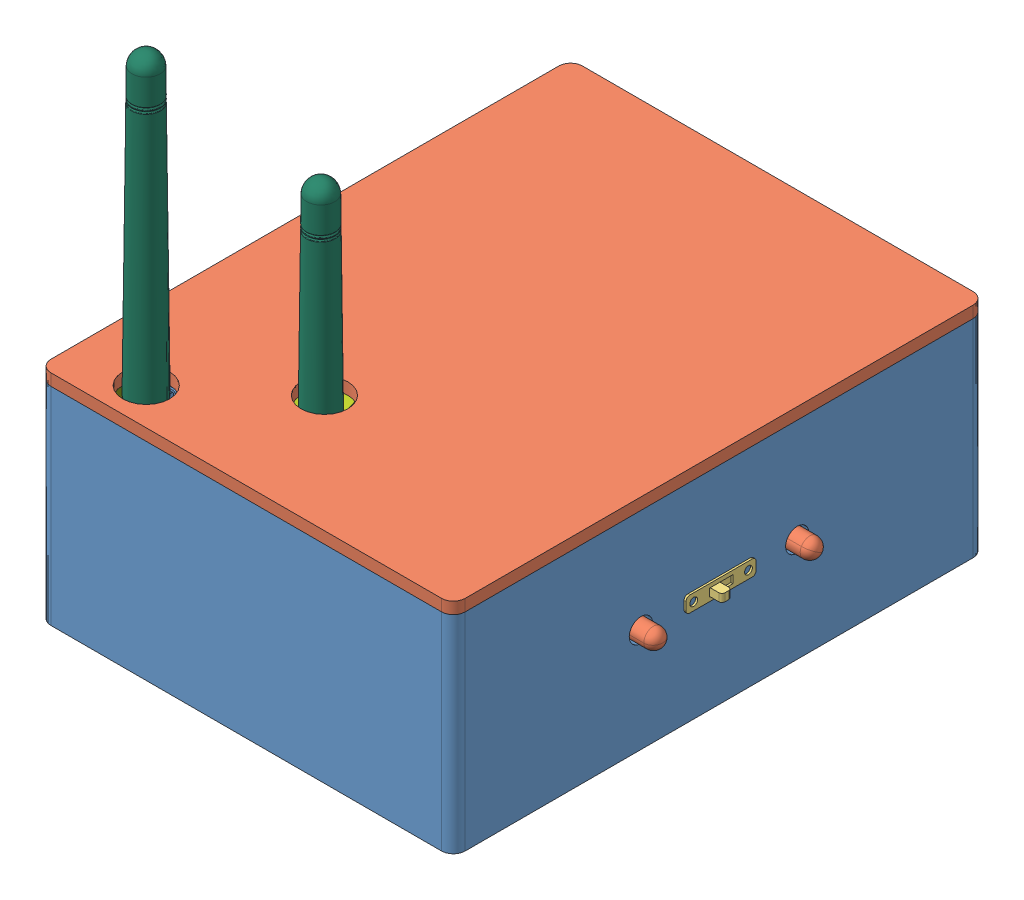
SolidWorks assembly antenna, configuration Défaut. Lengths in mm.
Overall size (111.65 135.1 136).
168 component instances, 75 part files, 26 mates.
Components (placement in the parent):
- lower_part_antenna-1: lower_part_antenna [Défaut] at (-3.6296 -22.8061 136) size (106 53 136)
- upper_part_antenna-1: upper_part_antenna [Défaut] at (-3.6296 27.1939 136) size (106 3 136)
- NUCLEO-F411RE.STEP-1: NUCLEO-F411RE.STEP [Défaut] at (-7.5295 -22.0211 161.2883) x (1 0 0) z (0 1 0) size (70 83.97 20.27)
  - NUCLEO-F411RE_PCB_Varsay_lan.STEP-1: NUCLEO-F411RE_PCB_Varsay_lan.STEP [Défaut] at origin size (70 82.5 1.5)
  - NUCLEO-F411RE_PCB_HOLEs_Varsay_lan.STEP-1: NUCLEO-F411RE_PCB_HOLEs_Varsay_lan.STEP [Défaut] at origin size (65.28 79.87 1.57)
  - NUCLEO-F411RE_PCB_TOP_Pads_Varsay_lan.STEP-1: NUCLEO-F411RE_PCB_TOP_Pads_Varsay_lan.STEP [Défaut] at origin size (59.94 77.1 0.04)
  - NUCLEO-F411RE_PCB_TOP_Solder_Varsay_lan.STEP-1: NUCLEO-F411RE_PCB_TOP_Solder_Varsay_lan.STEP [Défaut] at origin size (69.8 82.3 0.05)
  - NUCLEO-F411RE_PCB_BOTTOM_Pads_Varsay_lan.STEP-1: NUCLEO-F411RE_PCB_BOTTOM_Pads_Varsay_lan.STEP [Défaut] at origin size (31.1 70.87 0.04)
  - NUCLEO-F411RE_PCB_BOTTOM_Solder_Varsay_lan.STEP-1: NUCLEO-F411RE_PCB_BOTTOM_Solder_Varsay_lan.STEP [Défaut] at origin size (69.8 82.3 0.04)
  - NUCLEO-F411RE_PCB_TOP_Overlay_Varsay_lan.STEP-1: NUCLEO-F411RE_PCB_TOP_Overlay_Varsay_lan.STEP [Défaut] at origin size (68.09 77.67 0)
  - NUCLEO-F411RE_PCB_TOP_Designators_Varsay_lan.STEP-1: NUCLEO-F411RE_PCB_TOP_Designators_Varsay_lan.STEP [Défaut] at origin size (66.29 79.64 0)
  - NUCLEO-F411RE_PCB_BOTTOM_Overlay_Varsay_lan.STEP-1: NUCLEO-F411RE_PCB_BOTTOM_Overlay_Varsay_lan.STEP [Défaut] at origin size (40.11 80.77 0)
  - SAMTEC_SSQ-106-01-G-S_for_NUCLEO_Varsay_lan.STEP-1: SAMTEC_SSQ-106-01-G-S_for_NUCLEO_Varsay_lan.STEP [Défaut] at (-33.02 8.89 0.785) x (0 1 0) z (1 0 0) size (15.75 11.15 2.41)
  - SAMTEC_SSQ-108-01-G-S_for_NUCLEO_Varsay_lan.STEP-1: SAMTEC_SSQ-108-01-G-S_for_NUCLEO_Varsay_lan.STEP [Défaut] at (-33.02 29.21 0.785) x (0 1 0) z (1 0 0) size (20.83 11.15 2.41)
  - SAMTEC_SSQ-108-01-G-S_for_NUCLEO_Varsay_lan.STEP-2: SAMTEC_SSQ-108-01-G-S_for_NUCLEO_Varsay_lan.STEP [Défaut] at (15.24 11.43 0.785) x (0 1 0) z (1 0 0) size (20.83 11.15 2.41)
  - SAMTEC_SSQ-110-01-G-S_for_NUCLEO_Varsay_lan.STEP-1: SAMTEC_SSQ-110-01-G-S_for_NUCLEO_Varsay_lan.STEP [Défaut] at (15.24 35.814 0.785) x (0 1 0) z (1 0 0) size (25.91 11.15 2.41)
  - MOLEX_0678038020_for_NUCLEO.STEP-1: MOLEX_0678038020_for_NUCLEO.STEP [Défaut] at (3.1721 75.2975 0.785) x (-1 0 0) z (0 1 0) size (9.9 4.95 9)
  - SAMTEC_TSW-119-07-T-D_for_NUCLEO_Varsay_lan.STEP-1: SAMTEC_TSW-119-07-T-D_for_NUCLEO_Varsay_lan.STEP [Défaut] at (-39.37 25.4 0.785) x (0 -1 0) z (-1 0 0) size (48.26 17.95 5.08)
  - SAMTEC_TSW-119-07-T-D_for_NUCLEO_Varsay_lan.STEP-2: SAMTEC_TSW-119-07-T-D_for_NUCLEO_Varsay_lan.STEP [Défaut] at (21.59 25.4 0.785) x (0 -1 0) z (-1 0 0) size (48.26 17.95 5.08)
  - SAMTEC_TSW-102-07-T-S_for_NUCLEO_Varsay_lan.STEP-1: SAMTEC_TSW-102-07-T-S_for_NUCLEO_Varsay_lan.STEP [Défaut] at (-40.64 74.93 0.785) x (0 1 0) z (1 0 0) size (5.08 10.92 2.54)
  - SAMTEC_TSW-102-07-T-S_for_NUCLEO_Varsay_lan.STEP-2: SAMTEC_TSW-102-07-T-S_for_NUCLEO_Varsay_lan.STEP [Défaut] at (-31.75 59.055 0.785) x (0 -1 0) z (-1 0 0) size (5.08 10.92 2.54)
  - SAMTEC_TSW-102-07-T-S_for_NUCLEO_Varsay_lan.STEP-3: SAMTEC_TSW-102-07-T-S_for_NUCLEO_Varsay_lan.STEP [Défaut] at (-9.525 77.47 0.785) x (1 0 0) z (0 -1 0) size (5.08 10.92 2.54)
  - SAMTEC_TSW-102-07-T-S_for_NUCLEO_Varsay_lan.STEP-4: SAMTEC_TSW-102-07-T-S_for_NUCLEO_Varsay_lan.STEP [Défaut] at (-9.525 38.735 0.785) x (1 0 0) z (0 -1 0) size (5.08 10.92 2.54)
  - SAMTEC_TSW-102-07-T-S_for_NUCLEO_Varsay_lan.STEP-5: SAMTEC_TSW-102-07-T-S_for_NUCLEO_Varsay_lan.STEP [Défaut] at (22.86 74.93 0.785) x (0 -1 0) z (-1 0 0) size (5.08 10.92 2.54)
  - SAMTEC_TSW-103-07-T-S_for_NUCLEO_Varsay_lan.STEP-1: SAMTEC_TSW-103-07-T-S_for_NUCLEO_Varsay_lan.STEP [Défaut] at (1.905 45.085 0.785) x (1 0 0) z (0 -1 0) size (7.62 10.92 2.54)
  - SAMTEC_TSW-104-07-T-S_for_NUCLEO_Varsay_lan.STEP-1: SAMTEC_TSW-104-07-T-S_for_NUCLEO_Varsay_lan.STEP [Défaut] at (-21.59 73.66 0.785) x (0 1 0) z (1 0 0) size (10.16 10.92 2.54)
  - SAMTEC_TSW-106-07-T-S_for_NUCLEO_Varsay_lan.STEP-1: SAMTEC_TSW-106-07-T-S_for_NUCLEO_Varsay_lan.STEP [Défaut] at (-35.56 64.77 0.785) x (0 1 0) z (1 0 0) size (15.24 10.92 2.54)
  - MOLEX_90059-0007.STEP-1: MOLEX_90059-0007.STEP [Défaut] at (-21.59 76.2 5.75) x (0 1 0) z (1 0 0) size (5.1 4.85 2.54)
  - MOLEX_90059-0007.STEP-2: MOLEX_90059-0007.STEP [Défaut] at (-21.59 71.12 5.75) x (0 -1 0) z (-1 0 0) size (5.1 4.85 2.54)
  - ST_STM32F411RET6_Varsay_lan.STEP-1: ST_STM32F411RET6_Varsay_lan.STEP [Défaut] at (-11.4265 21.5935 0.785) x (-1 0 0) z (0 0 -1) size (12 12 1.6)
  - ST_STM32F103CBT6_Varsay_lan.STEP-1: ST_STM32F103CBT6_Varsay_lan.STEP [Défaut] at (-8.89 64.77 0.785) x (1 0 0) z (0 -1 0) size (9 1.6 9)
  - ESWITCH_TL3301SPF160QGBLK_Varsay_lan.STEP-1: ESWITCH_TL3301SPF160QGBLK_Varsay_lan.STEP [Défaut] at (-0.635 50.8 0.785) x (0 -1 0) z (-1 0 0) size (6 10.7 10)
  - ESWITCH_TL3301SPF160QGBLU_Varsay_lan.STEP-1: ESWITCH_TL3301SPF160QGBLU_Varsay_lan.STEP [Défaut] at (-17.145 50.8 0.785) x (0 1 0) z (1 0 0) size (6 10.7 10)
  - ST_STS7PF30L_Varsay_lan.STEP-1: ST_STS7PF30L_Varsay_lan.STEP [Défaut] at (17.145 60.325 0.785) x (-1 0 0) z (0 1 0) size (4.9 1.75 6)
  - ABRACON_ABL-8.000MHZ-B2_Varsay_lan.STEP-1: ABRACON_ABL-8.000MHZ-B2_Varsay_lan.STEP [Défaut] at (-18.41 63.4908 0.785) x (0 -1 0) z (-1 0 0) size (11.5 5.57 5)
  - ST_LD1117S50TR_Varsay_lan.STEP-1: ST_LD1117S50TR_Varsay_lan.STEP [Défaut] at (-14.6685 43.18 0.785) x (0 -1 0) z (-1 0 0) size (6.5 1.9 7)
  - ST_LD39050PU33R_Varsay_lan.STEP-1: ST_LD39050PU33R_Varsay_lan.STEP [Défaut] at (1.905 40.64 0.785) x (0 1 0) z (1 0 0) size (3 1 3)
  - ST_LD3985M33R_Varsay_lan.STEP-1: ST_LD3985M33R_Varsay_lan.STEP [Défaut] at (7.62 63.5 0.785) x (1 0 0) z (0 -1 0) size (2.95 1.45 2.8)
  - KEMET_T491B106K025AT_Varsay_lan.STEP-1: KEMET_T491B106K025AT_Varsay_lan.STEP [Défaut] at (-22.86 41.275 0.785) x (0 -1 0) z (-1 0 0) size (2.8 1.9 3.5)
  - ST_STPS2L30A_Varsay_lan.STEP-1: ST_STPS2L30A_Varsay_lan.STEP [Défaut] at (-22.86 45.085 0.785) x (0 1 0) z (1 0 0) size (2.58 2.3 5.07)
  - KEMET_T491A106K006AT7280_Varsay_lan.STEP-1: KEMET_T491A106K006AT7280_Varsay_lan.STEP [Défaut] at (-8.255 43.053 0.785) x (1 0 0) z (0 -1 0) size (1.6 1.6 3.2)
  - ABRACON_ABS25-32.768KHZ-6-T_Varsay_lan.STEP-1: ABRACON_ABS25-32.768KHZ-6-T_Varsay_lan.STEP [Défaut] at (-23.495 6.35 0.785) x (1 0 0) z (0 -1 0) size (8 2.66 4)
  - LUMEX_SML-LX2835IGC-TR.STEP-1: LUMEX_SML-LX2835IGC-TR.STEP [Défaut] at (16.51 73.66 0.785) x (1 0 0) z (0 -1 0) size (2.7 1.8 3.5)
  - MOLEX_90059-0007.STEP-3: MOLEX_90059-0007.STEP [Défaut] at (3.175 45.085 5.75) x (-1 0 0) z (0 1 0) size (5.1 4.85 2.54)
  - ST_BAT60JFILM_Varsay_lan.STEP-1: ST_BAT60JFILM_Varsay_lan.STEP [Défaut] at (-31.115 71.12 0.785) x (0 -1 0) z (-1 0 0) size (1.28 1.17 2.5)
  - ST_BAT60JFILM_Varsay_lan.STEP-2: ST_BAT60JFILM_Varsay_lan.STEP [Défaut] at (7.62 69.85 0.785) x (0 -1 0) z (-1 0 0) size (1.28 1.17 2.5)
  - NXP_BC847B,215.STEP-1: NXP_BC847B,215.STEP [Défaut] at (12.065 64.135 0.785) x (0 -1 0) z (-1 0 0) size (2.9 1.1 2.43)
  - ST_BAT60JFILM_Varsay_lan.STEP-3: ST_BAT60JFILM_Varsay_lan.STEP [Défaut] at (10.795 59.69 0.785) x (1 0 0) z (0 -1 0) size (1.28 1.17 2.5)
  - YAGEO_CC0805KKX7R7BB225.STEP-1: YAGEO_CC0805KKX7R7BB225.STEP [Défaut] at (0.127 23.495 0.785) x (0 -1 0) z (-1 0 0) size (1.58 1.29 4.06)
  - YAGEO_RC0603JR-070RL.STEP-1: YAGEO_RC0603JR-070RL.STEP [Défaut] at (17.145 67.945 0.785) x (1 0 0) z (0 -1 0) size (0.8 0.55 2.16)
  - YAGEO_RC0603JR-070RL.STEP-2: YAGEO_RC0603JR-070RL.STEP [Défaut] at (15.875 67.945 0.785) x (1 0 0) z (0 -1 0) size (0.8 0.55 2.16)
  - YAGEO_RC0603JR-070RL.STEP-3: YAGEO_RC0603JR-070RL.STEP [Défaut] at (14.605 67.945 0.785) x (1 0 0) z (0 -1 0) size (0.8 0.55 2.16)
  - YAGEO_RC0603JR-070RL.STEP-4: YAGEO_RC0603JR-070RL.STEP [Défaut] at (13.335 67.945 0.785) x (1 0 0) z (0 -1 0) size (0.8 0.55 2.16)
  - YAGEO_RC0603JR-070RL.STEP-5: YAGEO_RC0603JR-070RL.STEP [Défaut] at (12.065 67.945 0.785) x (1 0 0) z (0 -1 0) size (0.8 0.55 2.16)
  - YAGEO_RC0603JR-070RL.STEP-6: YAGEO_RC0603JR-070RL.STEP [Défaut] at (10.795 67.945 0.785) x (1 0 0) z (0 -1 0) size (0.8 0.55 2.16)
  - YAGEO_RC0603JR-070RL.STEP-7: YAGEO_RC0603JR-070RL.STEP [Défaut] at (12.7 59.7535 0.785) x (1 0 0) z (0 -1 0) size (0.8 0.55 2.16)
  - YAGEO_RC0603JR-070RL.STEP-8: YAGEO_RC0603JR-070RL.STEP [Défaut] at (4.445 67.945 0.785) x (1 0 0) z (0 -1 0) size (0.8 0.55 2.16)
  - YAGEO_RC0603JR-070RL.STEP-9: YAGEO_RC0603JR-070RL.STEP [Défaut] at (3.175 67.945 0.785) x (1 0 0) z (0 -1 0) size (0.8 0.55 2.16)
  - YAGEO_RC0603JR-070RL.STEP-10: YAGEO_RC0603JR-070RL.STEP [Défaut] at (1.905 67.945 0.785) x (1 0 0) z (0 -1 0) size (0.8 0.55 2.16)
  - YAGEO_RC0603JR-070RL.STEP-11: YAGEO_RC0603JR-070RL.STEP [Défaut] at (0 67.945 0.785) x (1 0 0) z (0 -1 0) size (0.8 0.55 2.16)
  - YAGEO_RC0603JR-070RL.STEP-12: YAGEO_RC0603JR-070RL.STEP [Défaut] at (-6.985 73.025 0.785) x (1 0 0) z (0 -1 0) size (0.8 0.55 2.16)
  - YAGEO_RC0603JR-070RL.STEP-13: YAGEO_RC0603JR-070RL.STEP [Défaut] at (-8.255 73.025 0.785) x (1 0 0) z (0 -1 0) size (0.8 0.55 2.16)
  - YAGEO_RC0603JR-070RL.STEP-14: YAGEO_RC0603JR-070RL.STEP [Défaut] at (-9.525 73.025 0.785) x (1 0 0) z (0 -1 0) size (0.8 0.55 2.16)
  - YAGEO_RC0603JR-070RL.STEP-15: YAGEO_RC0603JR-070RL.STEP [Défaut] at (-14.605 73.025 0.785) x (1 0 0) z (0 -1 0) size (0.8 0.55 2.16)
  - YAGEO_RC0603JR-070RL.STEP-16: YAGEO_RC0603JR-070RL.STEP [Défaut] at (-31.115 73.025 0.785) x (0 -1 0) z (-1 0 0) size (0.8 0.55 2.16)
  - YAGEO_RC0603JR-070RL.STEP-17: YAGEO_RC0603JR-070RL.STEP [Défaut] at (-31.115 69.215 0.785) x (0 -1 0) z (-1 0 0) size (0.8 0.55 2.16)
  - YAGEO_RC0603JR-070RL.STEP-18: YAGEO_RC0603JR-070RL.STEP [Défaut] at (-31.115 67.31 0.785) x (0 -1 0) z (-1 0 0) size (0.8 0.55 2.16)
  - YAGEO_RC0603JR-070RL.STEP-19: YAGEO_RC0603JR-070RL.STEP [Défaut] at (-31.115 65.405 0.785) x (0 -1 0) z (-1 0 0) size (0.8 0.55 2.16)
  - YAGEO_RC0603JR-070RL.STEP-20: YAGEO_RC0603JR-070RL.STEP [Défaut] at (-31.115 63.5 0.785) x (0 -1 0) z (-1 0 0) size (0.8 0.55 2.16)
  - YAGEO_RC0603JR-070RL.STEP-21: YAGEO_RC0603JR-070RL.STEP [Défaut] at (-25.4 64.77 0.785) x (0 -1 0) z (-1 0 0) size (0.8 0.55 2.16)
  - YAGEO_RC0603JR-070RL.STEP-22: YAGEO_RC0603JR-070RL.STEP [Défaut] at (-25.4 63.5 0.785) x (0 -1 0) z (-1 0 0) size (0.8 0.55 2.16)
  - YAGEO_RC0603JR-070RL.STEP-23: YAGEO_RC0603JR-070RL.STEP [Défaut] at (-25.4 62.23 0.785) x (0 -1 0) z (-1 0 0) size (0.8 0.55 2.16)
  - YAGEO_RC0603JR-070RL.STEP-24: YAGEO_RC0603JR-070RL.STEP [Défaut] at (-25.4 60.96 0.785) x (0 -1 0) z (-1 0 0) size (0.8 0.55 2.16)
  - YAGEO_RC0603JR-070RL.STEP-25: YAGEO_RC0603JR-070RL.STEP [Défaut] at (-15.875 11.43 0.785) x (1 0 0) z (0 -1 0) size (0.8 0.55 2.16)
  - YAGEO_RC0603JR-070RL.STEP-26: YAGEO_RC0603JR-070RL.STEP [Défaut] at (-14.605 11.43 0.785) x (1 0 0) z (0 -1 0) size (0.8 0.55 2.16)
  - YAGEO_RC0603JR-070RL.STEP-27: YAGEO_RC0603JR-070RL.STEP [Défaut] at (-22.225 18.415 0.785) x (1 0 0) z (0 -1 0) size (0.8 0.55 2.16)
  - YAGEO_RC0603JR-070RL.STEP-28: YAGEO_RC0603JR-070RL.STEP [Défaut] at (-20.955 32.385 0.785) x (0 -1 0) z (-1 0 0) size (0.8 0.55 2.16)
  - YAGEO_RC0603JR-070RL.STEP-29: YAGEO_RC0603JR-070RL.STEP [Défaut] at (-8.89 51.435 0.785) x (0 -1 0) z (-1 0 0) size (0.8 0.55 2.16)
  - YAGEO_RC0603JR-070RL.STEP-30: YAGEO_RC0603JR-070RL.STEP [Défaut] at (-8.89 47.625 0.785) x (0 -1 0) z (-1 0 0) size (0.8 0.55 2.16)
  - YAGEO_RC0603JR-070RL.STEP-31: YAGEO_RC0603JR-070RL.STEP [Défaut] at (3.81 36.83 0.785) x (0 -1 0) z (-1 0 0) size (0.8 0.55 2.16)
  - YAGEO_RC0603JR-070RL.STEP-32: YAGEO_RC0603JR-070RL.STEP [Défaut] at (0 63.5 0.785) x (0 -1 0) z (-1 0 0) size (0.8 0.55 2.16)
  - YAGEO_RC0603JR-070RL.STEP-33: YAGEO_RC0603JR-070RL.STEP [Défaut] at (0 62.23 0.785) x (0 -1 0) z (-1 0 0) size (0.8 0.55 2.16)
  - YAGEO_CC0603KRX7R7BB104.STEP-1: YAGEO_CC0603KRX7R7BB104.STEP [Défaut] at (-11.43 73.025 0.785) x (1 0 0) z (0 -1 0) size (0.8 0.8 2.16)
  - YAGEO_CC0603KRX7R7BB104.STEP-2: YAGEO_CC0603KRX7R7BB104.STEP [Défaut] at (-1.905 67.945 0.785) x (1 0 0) z (0 -1 0) size (0.8 0.8 2.16)
  - YAGEO_CC0603KRX7R7BB104.STEP-3: YAGEO_CC0603KRX7R7BB104.STEP [Défaut] at (5.08 62.865 0.785) x (1 0 0) z (0 -1 0) size (0.8 0.8 2.16)
  - YAGEO_CC0603KRX7R7BB104.STEP-4: YAGEO_CC0603KRX7R7BB104.STEP [Défaut] at (6.985 59.69 0.785) x (1 0 0) z (0 -1 0) size (0.8 0.8 2.16)
  - YAGEO_CC0603KRX7R7BB104.STEP-5: YAGEO_CC0603KRX7R7BB104.STEP [Défaut] at (8.89 59.69 0.785) x (1 0 0) z (0 -1 0) size (0.8 0.8 2.16)
  - YAGEO_CC0603KRX7R7BB104.STEP-6: YAGEO_CC0603KRX7R7BB104.STEP [Défaut] at (-21.59 62.23 0.785) x (1 0 0) z (0 -1 0) size (0.8 0.8 2.16)
  - YAGEO_CC0603KRX7R7BB104.STEP-7: YAGEO_CC0603KRX7R7BB104.STEP [Défaut] at (-21.59 64.77 0.785) x (1 0 0) z (0 -1 0) size (0.8 0.8 2.16)
  - YAGEO_CC0603KRX7R7BB104.STEP-8: YAGEO_CC0603KRX7R7BB104.STEP [Défaut] at (-15.24 63.5 0.785) x (1 0 0) z (0 -1 0) size (0.8 0.8 2.16)
  - YAGEO_CC0603KRX7R7BB104.STEP-9: YAGEO_CC0603KRX7R7BB104.STEP [Défaut] at (-6.35 58.42 0.785) x (0 -1 0) z (-1 0 0) size (0.8 0.8 2.16)
  - YAGEO_CC0603KRX7R7BB104.STEP-10: YAGEO_CC0603KRX7R7BB104.STEP [Défaut] at (-8.89 53.34 0.785) x (0 -1 0) z (-1 0 0) size (0.8 0.8 2.16)
  - YAGEO_CC0603KRX7R7BB104.STEP-11: YAGEO_CC0603KRX7R7BB104.STEP [Défaut] at (-8.89 49.53 0.785) x (0 -1 0) z (-1 0 0) size (0.8 0.8 2.16)
  - YAGEO_CC0603KRX7R7BB104.STEP-12: YAGEO_CC0603KRX7R7BB104.STEP [Défaut] at (-2.54 40.64 0.785) x (1 0 0) z (0 -1 0) size (0.8 0.8 2.16)
  - YAGEO_CC0603KRX7R7BB104.STEP-13: YAGEO_CC0603KRX7R7BB104.STEP [Défaut] at (-1.27 40.64 0.785) x (1 0 0) z (0 -1 0) size (0.8 0.8 2.16)
  - YAGEO_CC0603KRX7R7BB104.STEP-14: YAGEO_CC0603KRX7R7BB104.STEP [Défaut] at (5.08 40.64 0.785) x (1 0 0) z (0 -1 0) size (0.8 0.8 2.16)
  - YAGEO_CC0603KRX7R7BB104.STEP-15: YAGEO_CC0603KRX7R7BB104.STEP [Défaut] at (6.35 40.64 0.785) x (1 0 0) z (0 -1 0) size (0.8 0.8 2.16)
  - YAGEO_CC0603KRX7R7BB104.STEP-16: YAGEO_CC0603KRX7R7BB104.STEP [Défaut] at (-0.6033 27.94 0.785) x (0 -1 0) z (-1 0 0) size (0.8 0.8 2.16)
  - YAGEO_CC0603KRX7R7BB104.STEP-17: YAGEO_CC0603KRX7R7BB104.STEP [Défaut] at (-17.145 32.385 0.785) x (1 0 0) z (0 -1 0) size (0.8 0.8 2.16)
  - YAGEO_CC0603KRX7R7BB104.STEP-18: YAGEO_CC0603KRX7R7BB104.STEP [Défaut] at (-20.32 18.415 0.785) x (1 0 0) z (0 -1 0) size (0.8 0.8 2.16)
  - YAGEO_CC0603KRX7R7BB104.STEP-19: YAGEO_CC0603KRX7R7BB104.STEP [Défaut] at (-17.145 11.43 0.785) x (1 0 0) z (0 -1 0) size (0.8 0.8 2.16)
  - YAGEO_CC0603KRX7R7BB104.STEP-20: YAGEO_CC0603KRX7R7BB104.STEP [Défaut] at (0 17.78 0.785) x (0 -1 0) z (-1 0 0) size (0.8 0.8 2.16)
  - YAGEO_CC0603KRX7R7BB104.STEP-21: YAGEO_CC0603KRX7R7BB104.STEP [Défaut] at (-8.636 12.192 0.785) x (0 -1 0) z (-1 0 0) size (0.8 0.8 2.16)
  - YAGEO_CC0603KRX7R7BB104.STEP-22: YAGEO_CC0603KRX7R7BB104.STEP [Défaut] at (-19.685 2.794 0.785) x (0 -1 0) z (-1 0 0) size (0.8 0.8 2.16)
  - YAGEO_CC0603KRX7R7BB104.STEP-23: YAGEO_CC0603KRX7R7BB104.STEP [Défaut] at (-19.685 10.795 0.785) x (0 -1 0) z (-1 0 0) size (0.8 0.8 2.16)
  - LUMEX_SML-LX0603SRW-TR.STEP-1: LUMEX_SML-LX0603SRW-TR.STEP [Défaut] at (0.635 36.83 0.785) x (1 0 0) z (0 -1 0) size (2.17 0.59 0.81)
  - LUMEX_SML-LX0603GW-TR.STEP-1: LUMEX_SML-LX0603GW-TR.STEP [Défaut] at (-21.1455 35.5597 0.785) x (1 0 0) z (0 -1 0) size (2.17 0.59 0.81)
- User Library-R6_AA_UM3-1_5V_holder4AA-1: User Library-R6_AA_UM3-1_5V_holder4AA [4AA] at (-19.304 -4.2271 126.4024) x (1 0 0) z (0 1 0) size (59.56 61.47 15.11)
- Adafruit Ultimate GPS Logger Shield.stp-1: Adafruit Ultimate GPS Logger Shield.stp [Défaut] at (51.769 -14.4911 132.1764) x (0 0 1) z (-1 0 0) size (68.2 11.7 53.05)
  - microSD_Connector.stp-1: microSD_Connector.stp [Défaut] at (-28.4341 1.764 56.1048) x (0 0 -1) z (1 0 0) size (14.11 1.91 15.46)
    - microSD_Pin_11.35.stp-1: microSD_Pin_11.35.stp [Défaut] at (1.325 0 -2) x (0 0 1) z (-1 0 0) size (7.35 1.15 0.63)
    - microSD_Pin_11.15.stp-1: microSD_Pin_11.15.stp [Défaut] at (2.425 0 -2) x (0 0 1) z (-1 0 0) size (7.35 1.15 0.62)
    - microSD_Pin_11.15.stp-2: microSD_Pin_11.15.stp [Défaut] at (-1.975 0 -2) x (0 0 1) z (-1 0 0) size (7.35 1.15 0.62)
    - microSD_Cover.stp-1: microSD_Cover.stp [Défaut] at (0 1.7 0) x (1 0 0) z (0 0 -1) size (13.96 1.91 15.21)
    - microSD_Pin_11.35.stp-2: microSD_Pin_11.35.stp [Défaut] at (3.525 0 -2) x (0 0 1) z (-1 0 0) size (7.35 1.15 0.63)
    - microSD_Body.stp-1: microSD_Body.stp [Défaut] at origin size (14.1 1.85 15.2)
    - microSD_Pin_10.75.stp-1: microSD_Pin_10.75.stp [Défaut] at (-0.875 0 -2) x (0 0 1) z (-1 0 0) size (7.25 1.15 0.62)
    - microSD_Pin_11.15.stp-3: microSD_Pin_11.15.stp [Défaut] at (4.625 0 -2) x (0 0 1) z (-1 0 0) size (7.35 1.15 0.62)
    - microSD_Card_Detect.stp-1: microSD_Card_Detect.stp [Défaut] at (4.99 -0.05 7.4) size (4.45 1.91 2.06)
    - microSD_Pin_11.15.stp-4: microSD_Pin_11.15.stp [Défaut] at (5.725 0 -2) x (0 0 1) z (-1 0 0) size (7.35 1.15 0.62)
    - microSD_Pin_11.15.stp-5: microSD_Pin_11.15.stp [Défaut] at (0.225 0 -2) x (0 0 1) z (-1 0 0) size (7.35 1.15 0.62)
  - MODULO GPS_SMD.stp-1: MODULO GPS_SMD.stp [Défaut] at (-24.1111 1.764 72.4983) x (1 0 0) z (0 1 0) size (16 16 5.2)
    - FGPMMOPA6H_BASE.stp-1: FGPMMOPA6H_BASE.stp [Défaut] at origin size (16 16 2)
    - FGPMMOPA6H_TOP.stp-1: FGPMMOPA6H_TOP.stp [Défaut] at origin size (15 15 3)
  - SLIDE SWITCH DPDT_SMD.stp-1: SLIDE SWITCH DPDT_SMD.stp [Défaut] at (17.6649 1.764 51.831) x (0 0 1) z (0 1 0) size (6 7.2 3)
    - SLIDE SWITCH.stp-1: SLIDE SWITCH.stp [Défaut] at origin size (6 7.2 3)
  - 74HC4049_74HC4050.stp-1: 74HC4049_74HC4050.stp [Défaut] at (-15.3745 1.9423 51.4831) x (-1 0 0) z (0 1 0) size (5.85 10 1.8)
    - BODY.stp-1: BODY.stp [Défaut] at origin size (5.85 10 1.8)
  - SW3dPS-UFL-R-SMD.stp-1: SW3dPS-UFL-R-SMD.stp [Défaut] at (-34.458 1.764 65.7075) x (0 0 1) z (0 1 0) size (3.4 3.1 1.25)
    - SW3dPS-UFL-R-SMD_Part_578.stp-1: SW3dPS-UFL-R-SMD_Part_578.stp [Défaut] at origin size (0.6 0.5 0.1)
    - SW3dPS-UFL-R-SMD_Part_525.stp-1: SW3dPS-UFL-R-SMD_Part_525.stp [Défaut] at origin size (3 2.6 0.35)
    - SW3dPS-UFL-R-SMD_Part_555.stp-1: SW3dPS-UFL-R-SMD_Part_555.stp [Défaut] at origin size (0.6 0.5 0.1)
    - SW3dPS-UFL-R-SMD_Part_562.stp-1: SW3dPS-UFL-R-SMD_Part_562.stp [Défaut] at origin size (0.4 1.8 0.1)
    - SW3dPS-UFL-R-SMD_Part_739.stp-1: SW3dPS-UFL-R-SMD_Part_739.stp [Défaut] at origin size (2.01 2 0.91)
    - SW3dPS-UFL-R-SMD_Part_540.stp-1: SW3dPS-UFL-R-SMD_Part_540.stp [Défaut] at origin size (0.4 1.8 0.1)
  - MIC5225-3.3YM5.stp-1: MIC5225-3.3YM5.stp [Défaut] at (-12.2756 3.1697 88.6135) x (0 0 -1) z (0 1 0) size (3.05 3.05 1.3)
    - CHIP.stp-1: CHIP.stp [Défaut] at origin size (3.05 3.05 1.3)
  - PCB Adafruit Ultimate GPS Logger Shield.stp-1: PCB Adafruit Ultimate GPS Logger Shield.stp [Défaut] at (-36.508 0.214 94.725) size (68.2 1.56 53.05)
  - pins connection Shield.stp-1: pins connection Shield.stp [Défaut] at (-10.308 1.764 93.525) size (47.95 11.7 50.9)
  - Buton.stp-1: Buton.stp [Défaut] at (-34.4592 1.764 48.375) size (9.48 3.1 6.2)
  - SW3dPS-3002.stp-1: SW3dPS-3002.stp [Défaut] at (-26.3169 1.764 88.3628) x (-1 0 0) z (0 0 -1) size (18.44 2.78 12.04)
  - LED SMD.stp-1: LED SMD.stp [Défaut] at (-33.7112 1.764 69.9441) x (0 0 -1) z (0 1 0) size (3.21 1.61 1.15)
  - LED SMD.stp-2: LED SMD.stp [Défaut] at (-33.7112 1.764 75.4441) x (0 0 -1) z (0 1 0) size (3.21 1.61 1.15)
  - LED SMD.stp-3: LED SMD.stp [Défaut] at (-33.7112 1.764 80.9441) x (0 0 -1) z (0 1 0) size (3.21 1.61 1.15)
  - SMD RESISTOR-0805.stp-1: SMD RESISTOR-0805.stp [Défaut] at (-34.9121 2.064 84.7392) size (1.25 0.61 2)
  - SMD RESISTOR-0805.stp-2: SMD RESISTOR-0805.stp [Défaut] at (-14.0292 2.064 67.8714) size (1.25 0.61 2)
  - SMD RESISTOR-0805.stp-3: SMD RESISTOR-0805.stp [Défaut] at (-13.5461 2.064 63.138) x (0 0 -1) z (1 0 0) size (1.25 0.61 2)
  - SMD RESISTOR-0805.stp-4: SMD RESISTOR-0805.stp [Défaut] at (-17.3775 2.064 63.138) x (0 0 -1) z (1 0 0) size (1.25 0.61 2)
  - SMD CAPACITOR 0603.stp-1: SMD CAPACITOR 0603.stp [Défaut] at (-13.8958 2.164 92.2529) size (1.6 0.81 0.81)
  - SMD CAPACITOR 0603.stp-2: SMD CAPACITOR 0603.stp [Défaut] at (-13.8958 2.164 85.2529) size (1.6 0.81 0.81)
  - SMD CAPACITOR 0603.stp-3: SMD CAPACITOR 0603.stp [Défaut] at (-14.1323 2.164 79.4186) x (0 0 -1) z (1 0 0) size (1.6 0.81 0.81)
  - SMD CAPACITOR 0402.stp-1: SMD CAPACITOR 0402.stp [Défaut] at (-16.4867 2.014 83.0672) size (1.01 0.51 0.51)
- Antenna 868__F-1: Antenna 868__F [По умолчанию] at (-14.6706 -8.7271 173.8703) size (9.24 90.6 18.05)
- Antenna 868__F-2: Antenna 868__F [По умолчанию] at (-38.9296 17.6951 194.3331) x (0 0 -1) z (1 0 0) size (9.24 90.6 18.05)
- 433MhzRX-1: 433MhzRX [Défaut] at (-53.6296 20.3189 186) x (0 0 -1) z (1 0 0) size (30 19.01 6.8)
  - 433MhzRX.iges-1: 433MhzRX.iges [Défaut] at origin size (30 19.01 6.8)
    - 433 OOK Receiver.iges-1: 433 OOK Receiver.iges [Défaut] at origin size (30 19.01 6.8)
      - pcb.iges-1: pcb.iges [Défaut] at origin size (30 13.75 1.1)
      - small coil v1.iges-1: small coil v1.iges [Défaut] at (-21.2443 -21.3088 -0.1406) x (0.939693 0.34202 0) z (0.34202 -0.939693 0) size (3.59 4.14 3.27)
      - Frequency Selector.iges-1: Frequency Selector.iges [Défaut] at origin size (5 5 5.8)
      - Pin Headers.iges-1: Pin Headers.iges [Défaut] at origin size (10.79 8.27 4.29)
        - Pin Header Bendt v1.iges-1: Pin Header Bendt v1.iges [Défaut] at (-0.55 -6.5006 0.0858) x (1 0 0) z (0 -1 0) size (2.54 4.29 8.27)
        - Pin Header Bendt v1.iges-2: Pin Header Bendt v1.iges [Défaut] at (-3.3 -6.5006 0.0858) x (1 0 0) z (0 -1 0) size (2.54 4.29 8.27)
        - Pin Header Bendt v1.iges-3: Pin Header Bendt v1.iges [Défaut] at (-6.05 -6.5006 0.0858) x (1 0 0) z (0 -1 0) size (2.54 4.29 8.27)
        - Pin Header Bendt v1.iges-4: Pin Header Bendt v1.iges [Défaut] at (-8.8 -6.5006 0.0858) x (1 0 0) z (0 -1 0) size (2.54 4.29 8.27)
- LED_RGB.stp-1: LED_RGB.stp [Défaut] at (46.3704 0.6939 156) x (0 0.511967 -0.859005) z (1 0 0) size (5 4.9 35.65)
- LED_RGB.stp-2: LED_RGB.stp [Défaut] at (46.3704 0.6939 116) x (0 0 -1) z (1 0 0) size (5 4.9 35.65)
- Slide_Switch-1: Slide_Switch [Default] at (44.8704 0.6939 136) x (0 0 -1) z (0 -1 0) size (18 11.9 4)
Mates (geometry in assembly coordinates):
- Coïncidente1: coincident: plane of lower_part_antenna-1 through (-3.6296 -22.8061 136) normal (0 1 0); plane of NUCLEO-F411RE.STEP-1/NUCLEO-F411RE_PCB_BOTTOM_Solder_Varsay_lan.STEP-1 through (2.5805 -22.8061 106.2883) normal (0 -1 0)
- Coïncidente7: coincident: line of NUCLEO-F411RE.STEP-1/SAMTEC_SSQ-106-01-G-S_for_NUCLEO_Varsay_lan.STEP-1 through (-41.756 -12.7271 144.5243) axis (0 0 1); line of Adafruit Ultimate GPS Logger Shield.stp-1/pins connection Shield.stp-1 through (-41.756 -12.7271 144.7184) axis (0 0 1)
- Parallèle4: parallel: plane of NUCLEO-F411RE.STEP-1/SAMTEC_SSQ-108-01-G-S_for_NUCLEO_Varsay_lan.STEP-2 through (7.7105 -12.7271 149.8583) normal (0 1 0); plane of Adafruit Ultimate GPS Logger Shield.stp-1/PCB Adafruit Ultimate GPS Logger Shield.stp-1 through (-42.956 -14.2771 95.6684) normal (0 -1 0)
- Verrouiller2: lock: unknown of ?; unknown of ?
- Coïncidente14: coincident: plane of Adafruit Ultimate GPS Logger Shield.stp-1/PCB Adafruit Ultimate GPS Logger Shield.stp-1 through (-42.956 -12.7271 95.6684) normal (0 1 0); plane of Antenna 868__F-1 through (-12.3612 -12.7271 162.6203) normal (0 -1 0)
- Parallèle7: parallel: plane of Adafruit Ultimate GPS Logger Shield.stp-1/pins connection Shield.stp-1 through (-39.256 -4.2271 144.7184) normal (1 0 0); plane of Antenna 868__F-1 through (-17.9206 -11.9771 177.1203) normal (-1 0 0)
- Verrouiller3: lock: unknown of ?; unknown of Antenna 868__F-1
- Parallèle9: parallel: plane of lower_part_antenna-1 through (-3.6296 -22.8061 136) normal (0 1 0); plane of NUCLEO-F411RE.STEP-1/SAMTEC_TSW-119-07-T-D_for_NUCLEO_Varsay_lan.STEP-2 through (12.473 -30.8061 120.5061) normal (0 -1 0)
- Coïncidente23: coincident: plane of User Library-R6_AA_UM3-1_5V_holder4AA-1 through (-47.752 -4.2271 157.1364) normal (0 -1 0); plane of Adafruit Ultimate GPS Logger Shield.stp-1/pins connection Shield.stp-1 through (-41.756 -4.2271 121.8684) normal (0 1 0)
- Coïncidente24: coincident: plane of User Library-R6_AA_UM3-1_5V_holder4AA-1 through (-47.752 10.8859 95.6684) normal (0 0 -1); plane of Adafruit Ultimate GPS Logger Shield.stp-1/PCB Adafruit Ultimate GPS Logger Shield.stp-1 through (-42.956 -12.7271 95.6684) normal (0 0 -1)
- Coïncidente25: coincident: plane of User Library-R6_AA_UM3-1_5V_holder4AA-1 through (9.144 10.8859 95.6684) normal (1 0 0); plane of Adafruit Ultimate GPS Logger Shield.stp-1/pins connection Shield.stp-1 through (9.144 -4.2271 160.3684) normal (1 0 0)
- Tangent3: tangent: plane of lower_part_antenna-1 through (-53.6296 27.1939 71) normal (1 0 0); face of 433MhzRX-1/433MhzRX.iges-1/433 OOK Receiver.iges-1/pcb.iges-1
- Tangent4: tangent: plane of lower_part_antenna-1 through (-53.6296 27.1939 201) normal (0 0 -1); face of 433MhzRX-1/433MhzRX.iges-1/433 OOK Receiver.iges-1/pcb.iges-1
- Tangent5: tangent: line of lower_part_antenna-1 through (-53.6296 27.1939 71) axis (0 0 1); curve of 433MhzRX-1/433MhzRX.iges-1/433 OOK Receiver.iges-1/pcb.iges-1
- Tangent6: tangent: plane of Antenna 868__F-2 through (-52.6296 17.6951 194.3331) normal (-1 0 0); face of 433MhzRX-1/433MhzRX.iges-1/433 OOK Receiver.iges-1/pcb.iges-1
- Parallèle10: parallel: plane of lower_part_antenna-1 through (-3.6296 -22.8061 136) normal (0 1 0); plane of Antenna 868__F-2 through (-50.1796 13.6951 192.0237) normal (0 -1 0)
- Verrouiller4: lock: unknown of Antenna 868__F-2; unknown of ?
- Coïncidente27: coincident: plane of lower_part_antenna-1 through (46.3704 -1.3061 141) normal (0 1 0); plane of Slide_Switch-1 through (49.8704 -1.3061 141) normal (0 -1 0)
- Coïncidente28: coincident: plane of lower_part_antenna-1 through (46.3704 -1.3061 131) normal (0 0 1); plane of Slide_Switch-1 through (49.8704 2.6939 131) normal (0 0 -1)
- Coïncidente30: coincident: plane of lower_part_antenna-1 through (49.3704 27.1939 204) normal (1 0 0); plane of Slide_Switch-1 through (49.3704 -1.3061 145) normal (-1 0 0)
- Coaxiale1: concentric: cylinder of lower_part_antenna-1 through (46.3704 0.6939 156) axis (1 0 0) radius 3; cylinder of LED_RGB.stp-1 through (51.1954 0.6939 156) axis (-1 0 0) radius 2.45
- Coïncidente31: coincident: plane of lower_part_antenna-1 through (46.3704 27.1939 71) normal (-1 0 0); plane of LED_RGB.stp-1 through (46.3704 1.9482 153.8954) normal (-1 0 0)
- Coaxiale4: concentric: cylinder of lower_part_antenna-1 through (46.3704 0.6939 116) axis (1 0 0) radius 3; cylinder of LED_RGB.stp-2 through (51.1954 0.6939 116) axis (-1 0 0) radius 2.45
- Coïncidente32: coincident: plane of lower_part_antenna-1 through (46.3704 27.1939 71) normal (-1 0 0); plane of LED_RGB.stp-2 through (46.3704 0.6939 113.55) normal (-1 0 0)
- Coïncidente34: coincident: line of lower_part_antenna-1 through (-53.6296 27.1939 204) axis (1 0 0); line of upper_part_antenna-1 through (-53.6296 27.1939 204) axis (1 0 0)
- Coïncidente35: coincident: line of lower_part_antenna-1 through (-56.6296 27.1939 71) axis (0 0 1); line of upper_part_antenna-1 through (-56.6296 27.1939 71) axis (0 0 1)
